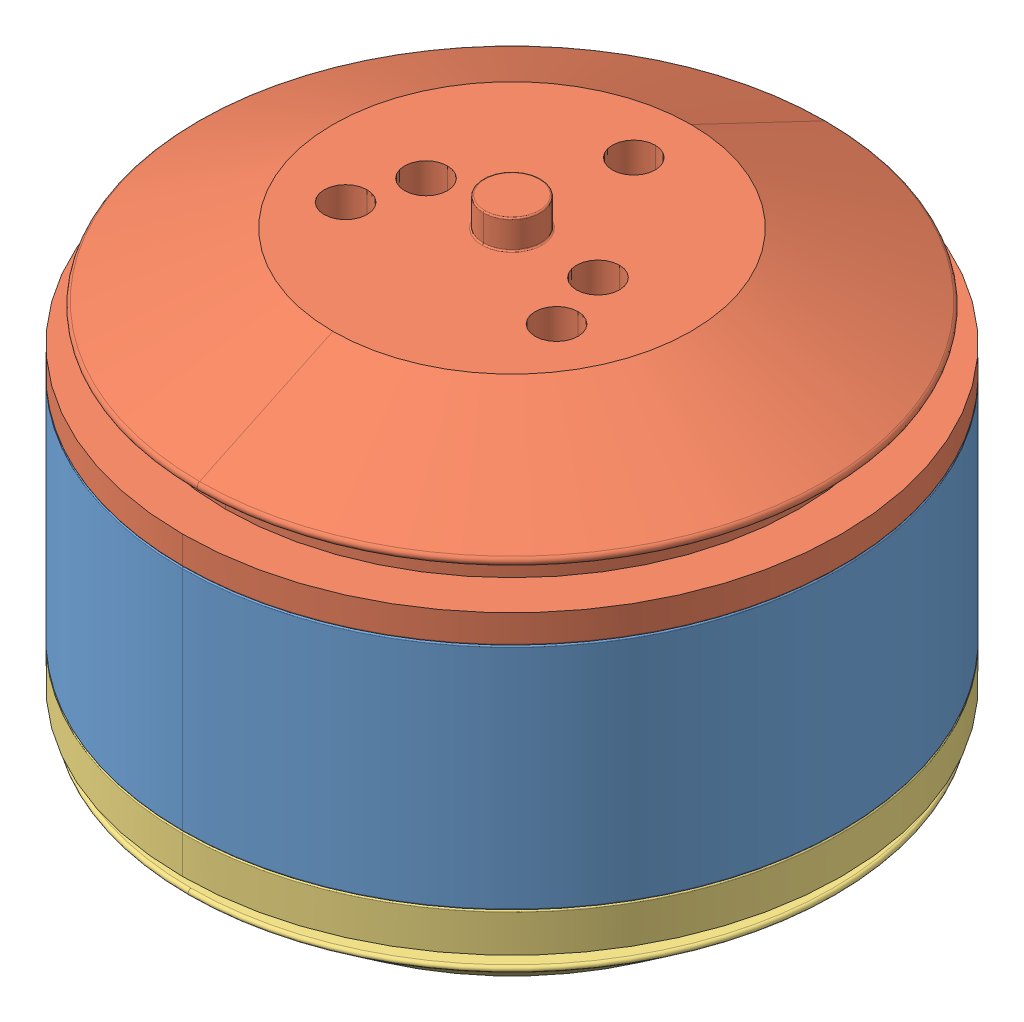
SolidWorks assembly 4114电机, configuration 默认. Lengths in mm.
Overall size (46 36.7 46).
4 component instances, 3 part files, 0 mates.
Components (placement in the parent):
- 4114电机.STEP-1: 4114电机.STEP [默认] at origin size (46 36.7 46)
  - ____3.STEP-1: ____3.STEP [默认] at (-1.2757 -9.9886 46) size (46 16 46)
  - ____2.STEP-1: ____2.STEP [默认] at (-1.2757 15.0114 46) size (46 11 46)
  - ____1.STEP-1: ____1.STEP [默认] at (-1.2757 -17.6886 46) x (-1 0 0) z (0 0 1) size (46 9.7 46)
